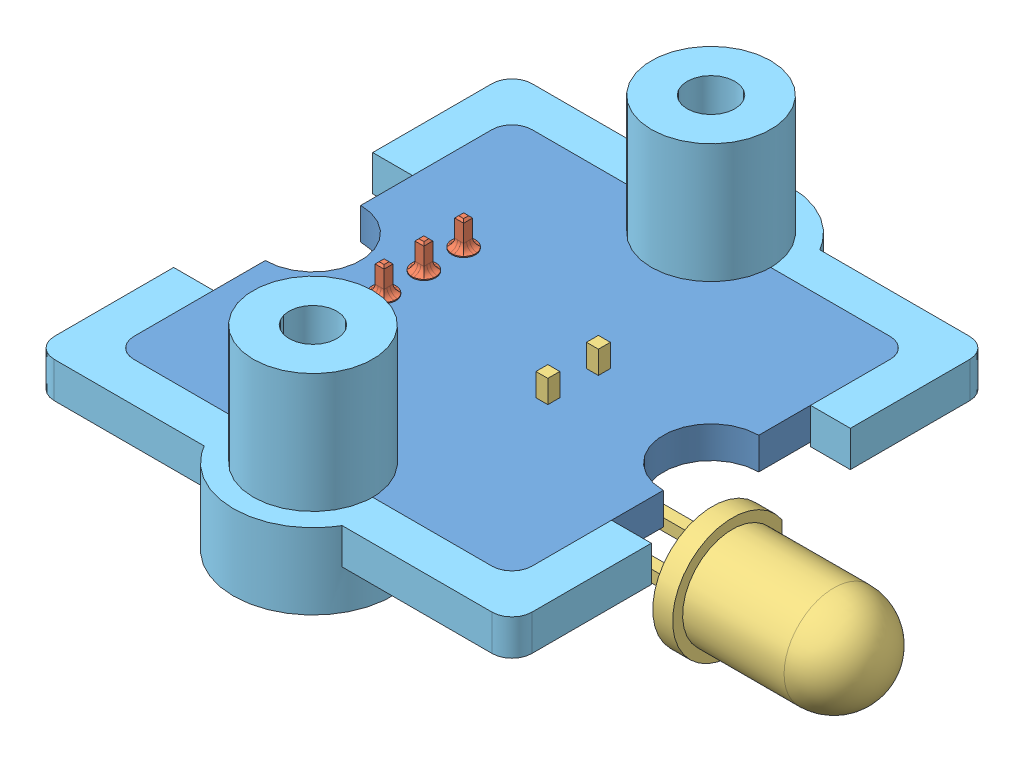
SolidWorks assembly ir_emett, configuration Défaut. Lengths in mm.
Overall size (30.67 15.6 28).
8 component instances, 5 part files, 11 mates.
Components (placement in the parent):
- Grove IR emetteur-1: Grove IR emetteur [Défaut] at (1.0913 1.195 28.6711) size (28.67 11 23.6)
  - PCB grove 20x20-1: PCB grove 20x20 [Défaut] at (-0.645 -0.7444 23.6) size (20 1.6 23.6)
  - Connecteur Grove (droit)-1: Connecteur Grove (droit) [Défaut] at (-3.3106 -0.7444 23.4632) x (0 0 1) z (1 0 0) size (10 11 5)
  - Led 5mm-1: Led 5mm [Défaut] at (9.4261 -4 23.6) x (1 0 0) z (0 -1 0) size (15.9 5.5 9)
- ecrou-h-1: ecrou-h [6007 HU M2] at (0.4463 0.4506 42.2711) x (0.866025 0 -0.5) z (0.5 0 0.866025) size (4 1.6 4.62)
- ecrou-h-2: ecrou-h [6007 HU M2] at (0.4463 0.4437 62.2711) x (0.866025 0 -0.5) z (0.5 0 0.866025) size (4 1.6 4.62)
- capuchon-grove-1: capuchon-grove [Défaut] at (0.4463 0.2506 57.2711) size (24 9.8 9)
- capuchon-grove-2: capuchon-grove [Défaut] at (0.4463 0.2506 47.2711) x (-1 0 0) z (0 0 -1) size (24 9.8 9)
Mates (geometry in assembly coordinates):
- Coaxiale1: concentric anti-aligned: cylinder of Grove IR emetteur-1/PCB grove 20x20-1 through (0.4463 2.0506 42.2711) axis (0 -1 0) radius 1.1; cylinder of ecrou-h-1 through (0.4463 -1.1494 42.2711) axis (0 1 0) radius 0.7835
- Coaxiale2: concentric anti-aligned: cylinder of Grove IR emetteur-1/PCB grove 20x20-1 through (0.4463 2.0506 62.2711) axis (0 -1 0) radius 1.1; cylinder of ecrou-h-2 through (0.4463 -1.1563 62.2711) axis (0 1 0) radius 0.7835
- Parallèle1: parallel aligned: plane of Grove IR emetteur-1/Connecteur Grove (droit)-1 through (-2.2192 -7.5494 57.1343) normal (0 0 1); plane of ecrou-h-2 through (-0.7084 -1.1563 64.2711) normal (0 0 1)
- Parallèle2: parallel aligned: plane of Grove IR emetteur-1/Connecteur Grove (droit)-1 through (-2.2192 -7.5494 47.1343) normal (0 0 -1); plane of ecrou-h-1 through (1.601 -1.1494 40.2711) normal (0 0 -1)
- Coïncidente7: coincident anti-aligned: plane of Grove IR emetteur-1/PCB grove 20x20-1 through (10.4463 2.0506 52.2711) normal (1 0 0); plane of capuchon-grove-1 through (10.4463 2.0506 57.2711) normal (-1 0 0)
- Coaxiale6: concentric aligned: cylinder of Grove IR emetteur-1/PCB grove 20x20-1 through (0.4463 2.0506 42.2711) axis (0 -1 0) radius 1.1; cylinder of capuchon-grove-2 through (0.4463 8.0506 42.2711) axis (0 -1 0) radius 1.2
- Coïncidente9: coincident anti-aligned: plane of Grove IR emetteur-1/PCB grove 20x20-1 through (10.4463 2.0506 52.2711) normal (1 0 0); plane of capuchon-grove-2 through (10.4463 2.0506 47.2711) normal (-1 0 0)
- Coïncidente12: coincident anti-aligned: plane of Grove IR emetteur-1/PCB grove 20x20-1 through (0.4463 0.4506 52.2711) normal (0 -1 0); plane of ecrou-h-1 through (1.601 0.4506 40.2711) normal (0 1 0)
- Coïncidente13: coincident anti-aligned: plane of Grove IR emetteur-1/PCB grove 20x20-1 through (0.4463 2.0506 52.2711) normal (0 1 0); plane of capuchon-grove-2 through (0.4463 2.0506 42.2711) normal (0 -1 0)
- Coïncidente14: coincident anti-aligned: plane of Grove IR emetteur-1/PCB grove 20x20-1 through (0.4463 2.0506 52.2711) normal (0 1 0); plane of capuchon-grove-1 through (0.4463 2.0506 62.2711) normal (0 -1 0)
- Coïncidente15: coincident anti-aligned: plane of Grove IR emetteur-1/PCB grove 20x20-1 through (0.4463 2.0506 62.2711) normal (0 0 1); plane of capuchon-grove-1 through (-1.5537 2.0506 62.2711) normal (0 0 -1)
